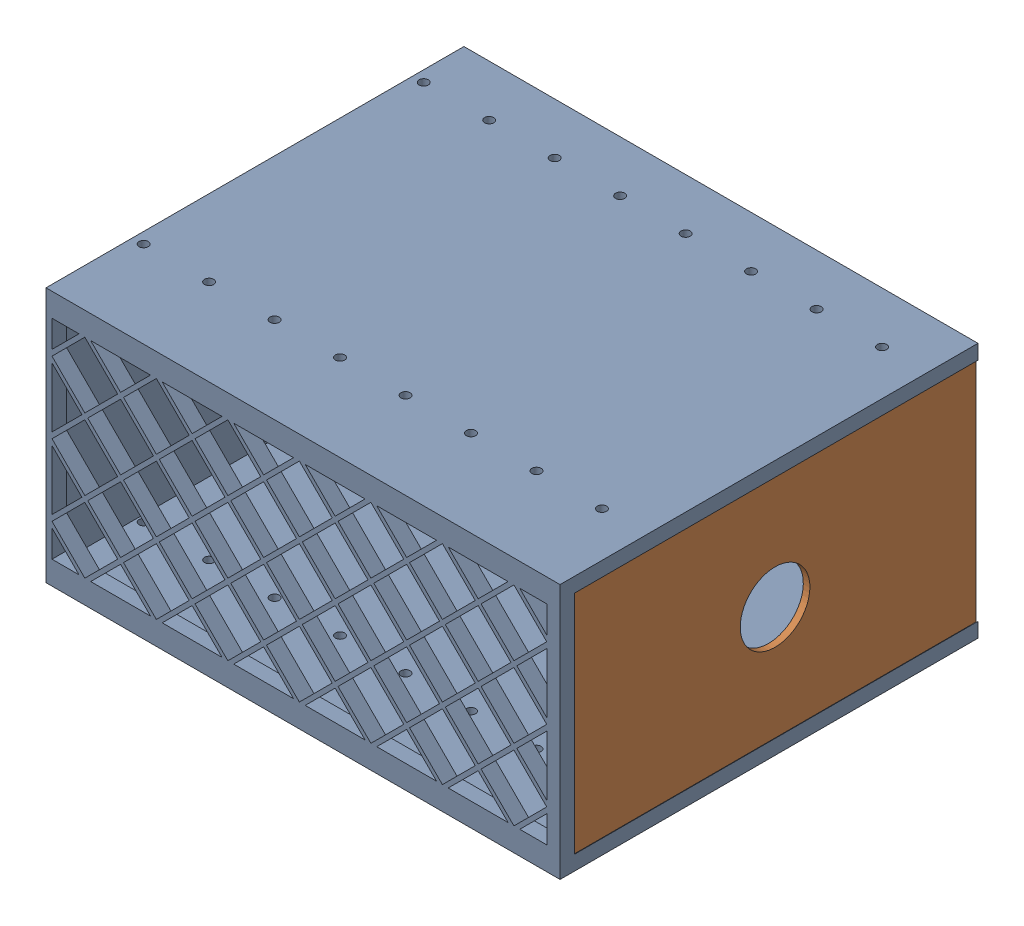
SolidWorks assembly Assembled, configuration Default. Lengths in mm.
Overall size (140.59 69.85 114.3).
2 component instances, 2 part files, 3 mates.
Components (placement in the parent):
- Drawer-1: Drawer [Default] at (-90.3277 -29.2151 64.0766) size (140.59 69.85 114.3)
- Lid-1: Lid [Default] at (48.2613 38.5099 -49.9234) x (0 -1 0) z (0 0 1) size (65.6 1.8 110)
Mates (geometry in assembly coordinates):
- Coincident2: coincident anti-aligned: plane of Drawer-1 through (48.2613 38.6349 125.957) normal (1 0 0); plane of Lid-1 through (48.2613 38.5099 60.0766) normal (-1 0 0)
- Width1: width aligned: plane of Lid-1 through (50.0613 36.7099 60.0766) normal (0.707107 0.707107 0); plane of Lid-1 through (48.2613 -27.0901 60.0766) normal (0.707107 -0.707107 0); plane of Drawer-1 through (48.2613 -27.2151 125.957) normal (-0.707107 0.707107 0); plane of Drawer-1 through (50.2613 36.6349 125.957) normal (-0.707107 -0.707107 0)
- Coincident3: coincident anti-aligned: plane of Drawer-1 through (-207.7392 36.6349 60.0766) normal (0 0 -1); plane of Lid-1 through (48.2613 38.5099 60.0766) normal (0 0 1)
